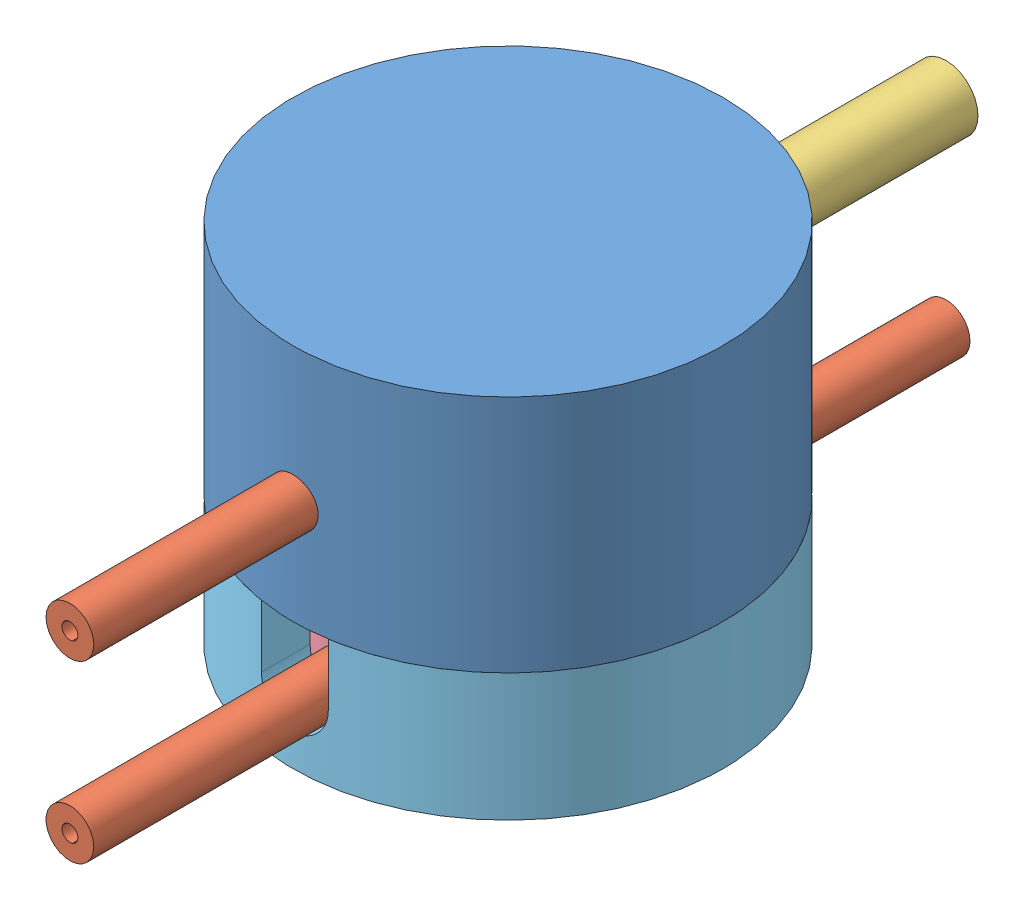
SolidWorks assembly 3D view live box 1, configuration Assemblata. Lengths in mm.
Overall size (27 23 55).
12 component instances, 8 part files, 10 mates.
Components (placement in the parent):
- 3Dview-Top-1: 3Dview-Top [Default] at (-2.6946 -4.6013 0) size (27 15 55)
  - Top-1: Top [Default] at origin size (27 15 27)
  - 3x1-1: 3x1 [Default] at (0 6.5 7.5) x (0.999962 0.00877 0) z (0 0 1) size (3 3 20)
  - 4x2-1: 4x2 [Default] at (0 8 -27.5) size (4 4 20)
- 3Dview-Inner bottom-1: 3Dview-Inner bottom [Default] at (-2.6946 -11.6013 0) x (0 0 -1) z (1 0 0) size (55 6.7 21)
  - Inner bottom-1: Inner bottom [Default] at origin size (21 6.7 21)
  - 3x1-2: 3x1 [Default] at (-7.5 2.5 0) x (0 0.981723 0.190315) z (-1 0 0) size (3 3 20)
  - 3x1-4: 3x1 [Default] at (27.5 2.5 0) x (0 -0.991525 0.129918) z (-1 0 0) size (3 3 20)
- Bottom-1: Bottom [Default] at (-2.6946 -12.6013 0) x (0 0 -1) z (1 0 0) size (27 8 27)
- Inner up-1: Inner up [Default] at (-2.6946 -6.6013 0) size (21 4.9 21)
- glass bottom-1: glass bottom [Default] at (-2.6946 -11.6013 0) size (21 0.3 21)
- Membrane-1: Membrane [Default] at (-2.6946 -6.6013 0) size (19 0.1 19)
Mates (geometry in assembly coordinates):
- Parallelo1: parallel aligned: line of 3Dview-Inner bottom-1/Inner bottom-1 through (7.8054 -11.6013 0) axis (-1 0 0); line of Bottom-1 through (10.8054 -12.6013 0) axis (-1 0 0)
- Concentrico3: concentric aligned: circle of 3Dview-Top-1/Top-1; circle of 3Dview-Inner bottom-1/Inner bottom-1
- Coincidente3: coincident anti-aligned: plane of 3Dview-Top-1/Top-1 through (-2.6946 -4.6013 0) normal (0 -1 0); plane of Bottom-1 through (-2.6946 -4.6013 0) normal (0 1 0)
- Parallelo2: parallel anti-aligned: plane of 3Dview-Top-1/3x1-1 through (-2.6946 1.8987 27.5) normal (0 0 1); plane of 3Dview-Inner bottom-1/3x1-4 through (-2.6946 -9.1013 -27.5) normal (0 0 -1)
- Concentrico5: concentric anti-aligned: circle of 3Dview-Inner bottom-1/Inner bottom-1; circle of glass bottom-1
- Coincidente4: coincident anti-aligned: plane of 3Dview-Inner bottom-1/Inner bottom-1 through (-2.6946 -11.3013 0) normal (0 -1 0); plane of glass bottom-1 through (-2.6946 -11.3013 0) normal (0 1 0)
- Concentrico6: concentric anti-aligned: circle of 3Dview-Inner bottom-1/Inner bottom-1; circle of Bottom-1
- Coincidente5: coincident anti-aligned: circle of Bottom-1; plane of glass bottom-1 through (-2.6946 -11.6013 0) normal (0 -1 0)
- Concentrico7: concentric aligned: circle of 3Dview-Inner bottom-1/Inner bottom-1; circle of Membrane-1
- Coincidente6: coincident anti-aligned: plane of 3Dview-Inner bottom-1/Inner bottom-1 through (-2.6946 -6.6013 0) normal (0 1 0); plane of Membrane-1 through (-2.6946 -6.6013 0) normal (0 -1 0)
